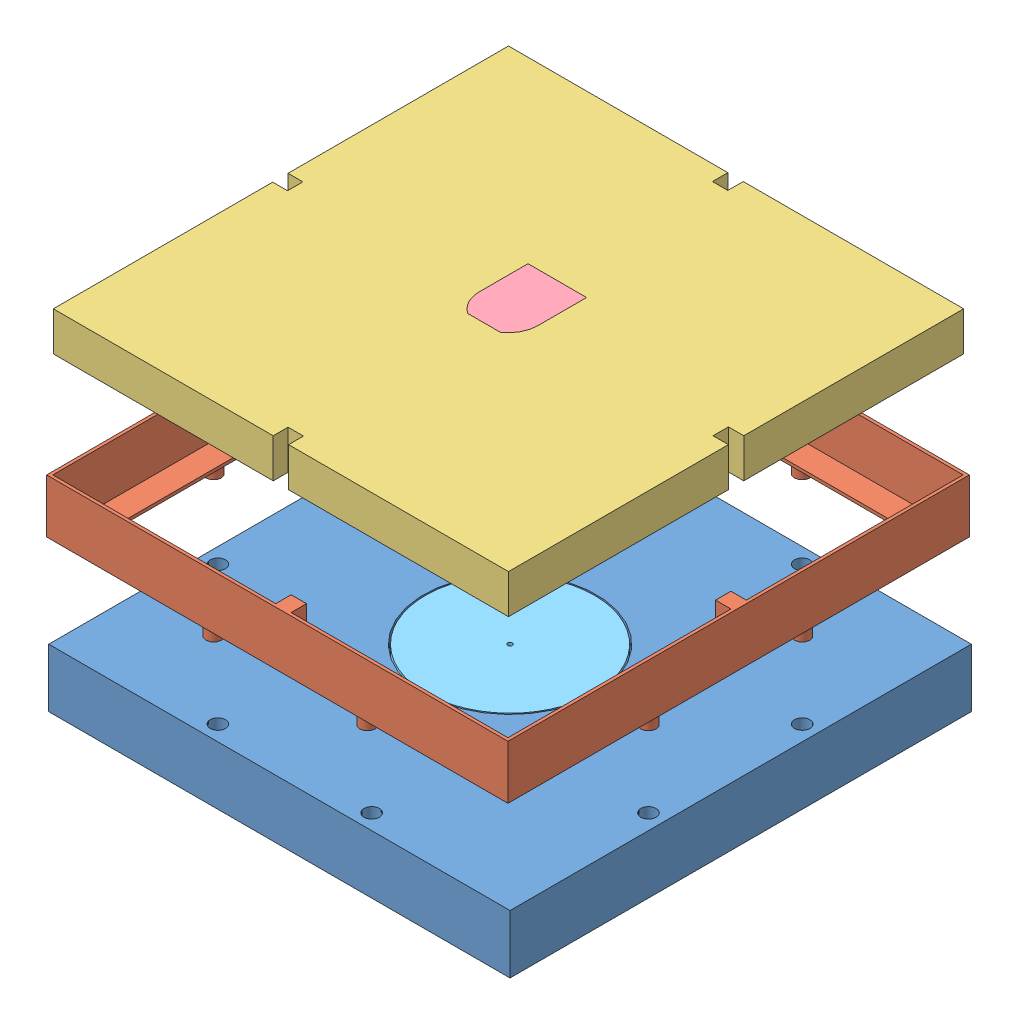
SolidWorks assembly dropmount assem_ag, configuration Default. Lengths in mm.
Overall size (150.68 113.18 150).
5 component instances, 5 part files, 9 mates.
Components (placement in the parent):
- base-1: base [Default] at origin size (150 19 150)
- rails-1: rails [Default] at (74.3218 66.323 -75) x (0 0 -1) z (1 0 0) size (150 22.48 150)
- testmotor topmount-1: testmotor topmount [Default] at (0.4885 100.4803 -1.0063) size (148 12.7 148)
- testmotor with holder-1: testmotor with holder [Default] at (74.4885 113.1803 -75.0063) x (-1 0 0) z (0 0 1) size (19.05 20.96 23.81)
- flywheel-1: flywheel [Default] at (75 16 -75) size (55 3 55)
Mates (geometry in assembly coordinates):
- Coincident12: coincident anti-aligned: plane of testmotor topmount-1 through (0.4885 100.4803 -67.0688) normal (0 0 -1); plane of testmotor with holder-1 through (74.4885 106.8303 -67.0688) normal (0 0 1)
- Coincident13: coincident anti-aligned: line of testmotor topmount-1 through (69.2234 113.1803 -67.0688) axis (1 0 0); line of testmotor with holder-1 through (79.7537 113.1803 -67.0688) axis (-1 0 0)
- Coincident14: coincident aligned: line of testmotor topmount-1 through (64.9635 113.1803 -75.0063) axis (0 0 -1); line of testmotor with holder-1 through (64.9635 113.1803 -75.0063) axis (0 0 -1)
- Concentric6: concentric anti-aligned: circle of base-1; circle of rails-1
- Concentric7: concentric anti-aligned: circle of base-1; circle of rails-1
- Coincident26: coincident anti-aligned: plane of rails-1 through (5.3218 66.323 -75) normal (1 0 0); plane of testmotor topmount-1 through (5.3218 100.4803 -77.327) normal (-1 0 0)
- Coincident27: coincident anti-aligned: plane of rails-1 through (74.3218 66.323 -144) normal (0 0 1); plane of testmotor topmount-1 through (76.8156 100.4803 -144) normal (0 0 -1)
- Coincident28: coincident anti-aligned: plane of base-1 through (75 16 -75) normal (0 1 0); plane of flywheel-1 through (75 16 -75) normal (0 -1 0)
- Concentric8: concentric aligned: circle of base-1; circle of flywheel-1
